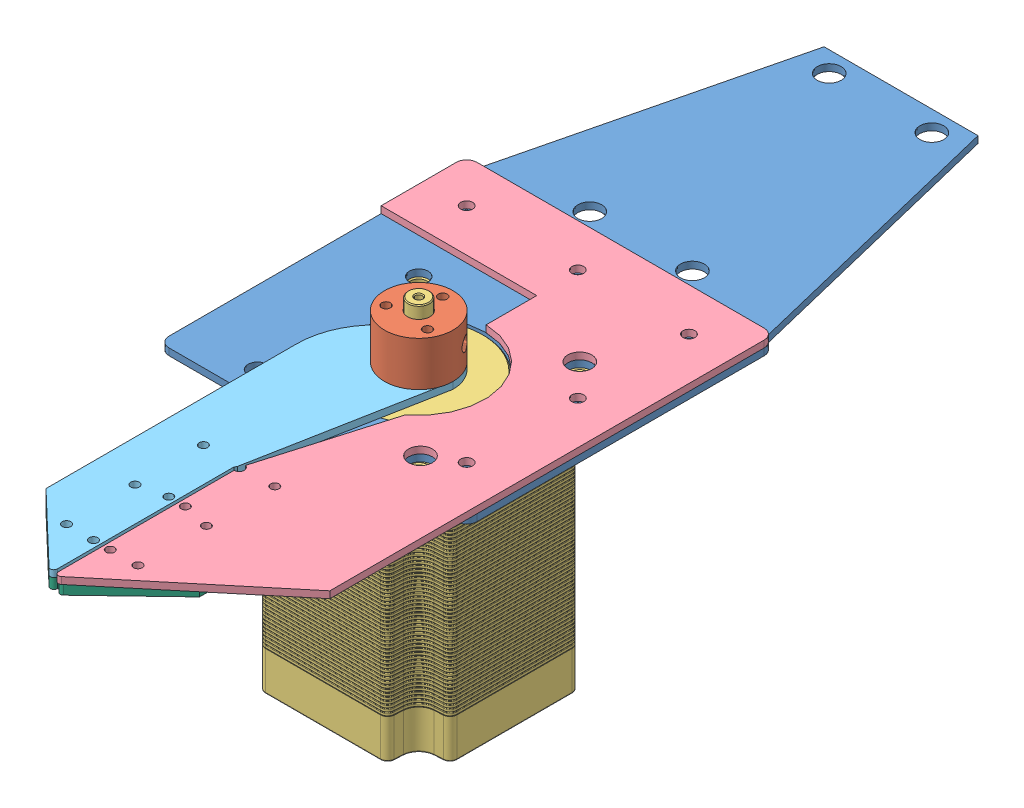
SolidWorks assembly Сборка — копия (2), configuration По умолчанию. Lengths in mm.
Overall size (90 95 247.87).
8 component instances, 7 part files, 24 mates.
Components (placement in the parent):
- Copy of Copy of Деталь001^Сборка — копия (2)-1: Copy of Copy of Деталь001^Сборка — копия (2) [По умолчанию] at origin size (90 2 172) (virtual)
- Part1-3: Part1 [По умолчанию] at (0 4 100) x (-0.5 0 -0.866025) z (0.866025 0 -0.5) size (20 13 20)
- Steppe motor Nema 23-2: Steppe motor Nema 23 [Default] at (33.8155 -53.5622 86.464) x (-1 0 0) z (0 1 0) size (58.5 57.12 95)
- Неподвижный финал-3: Неподвижный финал [По умолчанию] at (12.0454 2 75.1949) size (90 2 165.87)
- подвижная часть финал-1: подвижная часть финал [По умолчанию] at (0 2 100) x (0 0 -1) z (1 0 0) size (116.3 2 32.38)
- Резинка-1: Резинка [По умолчанию] at (0 2 100) x (0 0 1) z (0 -1 0) size (61 22.51 3)
- Резинка-2: Резинка [По умолчанию] at (0.125 -1 100) x (0 0 1) z (0 1 0) size (61 22.51 3)
- Прижимная_планка-1: Прижимная_планка [По умолчанию] at (0 -1 100) x (0 0 1) z (0 -1 0) size (57.56 17.01 1)
Mates (geometry in assembly coordinates):
- Concentric8: concentric aligned: circle of Copy of Copy of Деталь001^Сборка — копия (2)-1; circle of Steppe motor Nema 23-2
- Parallel2: parallel aligned: plane of Copy of Copy of Деталь001^Сборка — копия (2)-1 through (0 2 131) normal (0 0 1); plane of Steppe motor Nema 23-2 through (0 0 128) normal (0 0 1)
- Coincident3: coincident anti-aligned: plane of Copy of Copy of Деталь001^Сборка — копия (2)-1 through (0 0 0) normal (0 -1 0); plane of Steppe motor Nema 23-2 through (0 0 100) normal (0 1 0)
- Concentric9: concentric aligned: cylinder of Part1-3 through (0 24 100) axis (0 -1 0) radius 3.25; cylinder of Steppe motor Nema 23-2 through (0 20.5 100) axis (0 -1 0) radius 3.15
- Концентричный1: concentric anti-aligned: circle of Copy of Copy of Деталь001^Сборка — копия (2)-1; cylinder of Неподвижный финал-3 through (-32.5 4 53.5) axis (0 -1 0) radius 1.75
- Концентричный2: concentric aligned: cylinder of Copy of Copy of Деталь001^Сборка — копия (2)-1 through (32.5 2 53.5) axis (0 -1 0) radius 1.25; cylinder of Неподвижный финал-3 through (32.5 4 53.5) axis (0 -1 0) radius 1.75
- Совпадение1: coincident anti-aligned: plane of Copy of Copy of Деталь001^Сборка — копия (2)-1 through (0 2 0) normal (0 1 0); plane of Неподвижный финал-3 through (12.0454 2 75.1949) normal (0 -1 0)
- Концентричный3: concentric aligned: circle of Steppe motor Nema 23-2; cylinder of ? through (0 7.5 100) axis (0 -1 0) radius 3.5
- Концентричный4: concentric anti-aligned: cylinder of Part1-3 through (6.0621 7.5 103.5002) axis (0 1 0) radius 1.3; cylinder of ? through (6.0621 7.5 103.5002) axis (0 -1 0) radius 1.75
- Совпадение2: coincident aligned: circle of Part1-3; plane of ? through (0 7.5 100) normal (0 1 0)
- Расстояние1: distance = 0.5 mm anti-aligned: plane of ? through (0 5.5 100) normal (0 -1 0); plane of Copy of Copy of Деталь001^Сборка — копия (2)-1 through (0 5 0) normal (0 1 0)
- Параллельность1: parallel anti-aligned: line of Неподвижный финал-3 through (0 5 131) axis (-0.000033 0 1); line of ? through (-0.0035 7.5 208) axis (0.000033 0 -1)
- Концентричный5: concentric aligned: circle of Steppe motor Nema 23-2; cylinder of подвижная часть финал-1 through (0 4 100) axis (0 -1 0) radius 3.5
- Концентричный6: concentric aligned: circle of Part1-3; circle of подвижная часть финал-1
- Совпадение3: coincident anti-aligned: plane of Part1-3 through (0 4 100) normal (0 -1 0); plane of подвижная часть финал-1 through (0 4 100) normal (0 1 0)
- Совпадение4: coincident aligned: plane of Неподвижный финал-3 through (12.0454 2 75.1949) normal (0 -1 0); plane of подвижная часть финал-1 through (0 2 100) normal (0 -1 0)
- На месте1: in place: plane of подвижная часть финал-1 through (0 2 100) normal (0 -1 0); plane of ? through (0 2 0) normal (0 -1 0); moOrthogonalPlaneRef_w of подвижная часть финал-1 through (0 2 100) normal (0 -1 0); unknown of ?; plane of подвижная часть финал-1 through (0 2 100) normal (0 -1 0); unknown of ?; plane of подвижная часть финал-1 through (0 2 100) normal (0 -1 0); unknown of Резинка-1
- Совпадение5: coincident aligned: plane of подвижная часть финал-1; plane of Резинка-1
- Совпадение6: coincident aligned: moOrthogonalPlaneRef_w of подвижная часть финал-1 through (0 2 100) normal (-1 0 0); plane of Резинка-1
- Совпадение7: coincident anti-aligned: moOrthogonalPlaneRef_w of подвижная часть финал-1 through (0 2 100) normal (0 0 -1); plane of Резинка-1
- На месте2: in place: plane of Резинка-1 through (-1.375 -1 205.3014) normal (0 -1 0); plane of ? through (0 -1 0) normal (0 -1 0); plane of Резинка-1 through (-1.375 -1 205.3014) normal (0 -1 0); unknown of ?; plane of Резинка-1 through (-1.375 -1 205.3014) normal (0 -1 0); unknown of ?; plane of Резинка-1 through (-1.375 -1 205.3014) normal (0 -1 0); unknown of Прижимная_планка-1
- Совпадение8: coincident aligned: plane of Резинка-1; plane of Прижимная_планка-1
- Совпадение9: coincident aligned: moOrthogonalPlaneRef_w of Резинка-1 through (0 -1 100) normal (-1 0 0); plane of Прижимная_планка-1
- Совпадение10: coincident anti-aligned: moOrthogonalPlaneRef_w of Резинка-1 through (0 -1 100) normal (0 0 -1); plane of Прижимная_планка-1
